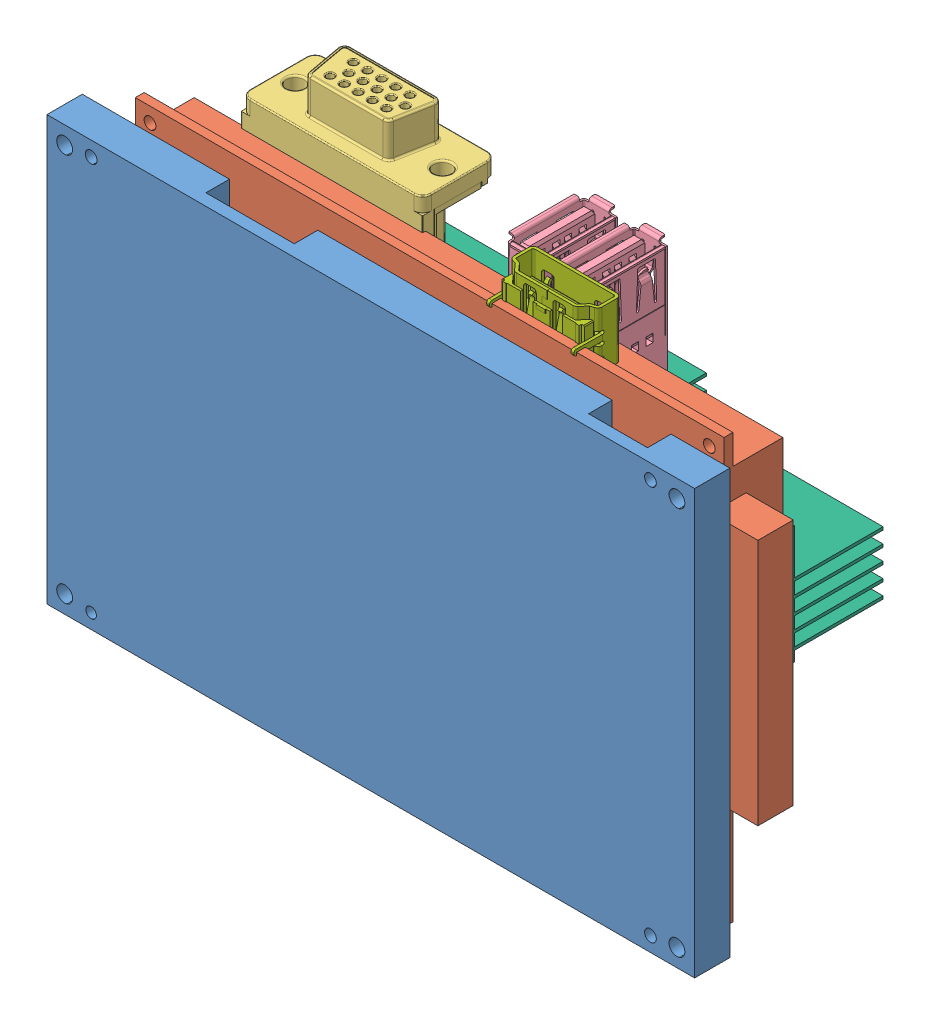
SolidWorks assembly Epia830A-With-Support, configuration Défaut. Lengths in mm.
Overall size (113 77.9 37).
10 component instances, 8 part files, 3 mates.
Components (placement in the parent):
- Epia830A-Support-1: Epia830A-Support [Défaut] at (-67.124 -42.5559 107) size (110 72 6)
- Epia830A-1: Epia830A [Défaut] at (7.7153 -11.2096 202.25) x (1 0 0) z (0 0 -1) size (108 77.9 34.25)
  - Epia830A-1: Epia830A [Défaut] at (-69.8392 -40.6536 99.25) size (108 72 12.25)
  - HDL 15-SL-B-1: HDL 15-SL-B [По умолчанию] at (-45.9392 -40.6536 115.025) x (-1 0 0) z (0 1 0) size (30.8 16.47 22.2)
  - USB-A 111 (vertical on plate)-1: USB-A 111 (vertical on plate) [По умолчанию] at (-10.7453 -27.6536 116.1) x (0 -1 0) z (0 0 -1) size (19.3 7.1 18.4)
  - USB-A 111 (vertical on plate)-2: USB-A 111 (vertical on plate) [По умолчанию] at (-2.2453 -27.6536 116.1) x (0 -1 0) z (0 0 -1) size (19.3 7.1 18.4)
  - DDR2 SO-DIMM-1: DDR2 SO-DIMM [1.5V] at (-31.0392 21.3464 93.75) x (1 0 0) z (0 1 0) size (67.6 3.5 30)
  - Epia830A-Dissipator-1: Epia830A-Dissipator [Défaut] at (-69.8392 -21.6536 109.25) size (100 40 17)
  - RJ45.ipt-1: RJ45.ipt [Défaut] at (14.2233 -40.6536 116.108) x (-1 0 0) z (0 -1 0) (suppressed, hidden)
  - HDMI_Socket-1: HDMI_Socket [Défaut] at (-2.3392 -45.2235 100.6) x (1 0 0) z (0 -1 0) size (15.14 8.38 12.15)
Mates (geometry in assembly coordinates):
- Distance1: distance = 4 mm anti-aligned: plane of Epia830A-Support-1 through (-67.124 -42.5559 107) normal (0 0 -1); plane of Epia830A-1/Epia830A-1 through (-62.124 29.4441 103) normal (0 0 1)
- Coïncidente1: coincident aligned: plane of Epia830A-Support-1 through (-67.124 29.4441 113) normal (0 1 0); plane of Epia830A-1/Epia830A-1 through (37.876 29.4441 101.5) normal (0 1 0)
- Coaxiale3: concentric aligned: cylinder of Epia830A-Support-1 through (-59.624 26.9441 107) axis (0 0 1) radius 1; cylinder of Epia830A-1/Epia830A-1 through (-59.624 26.9441 101.5) axis (0 0 1) radius 1
